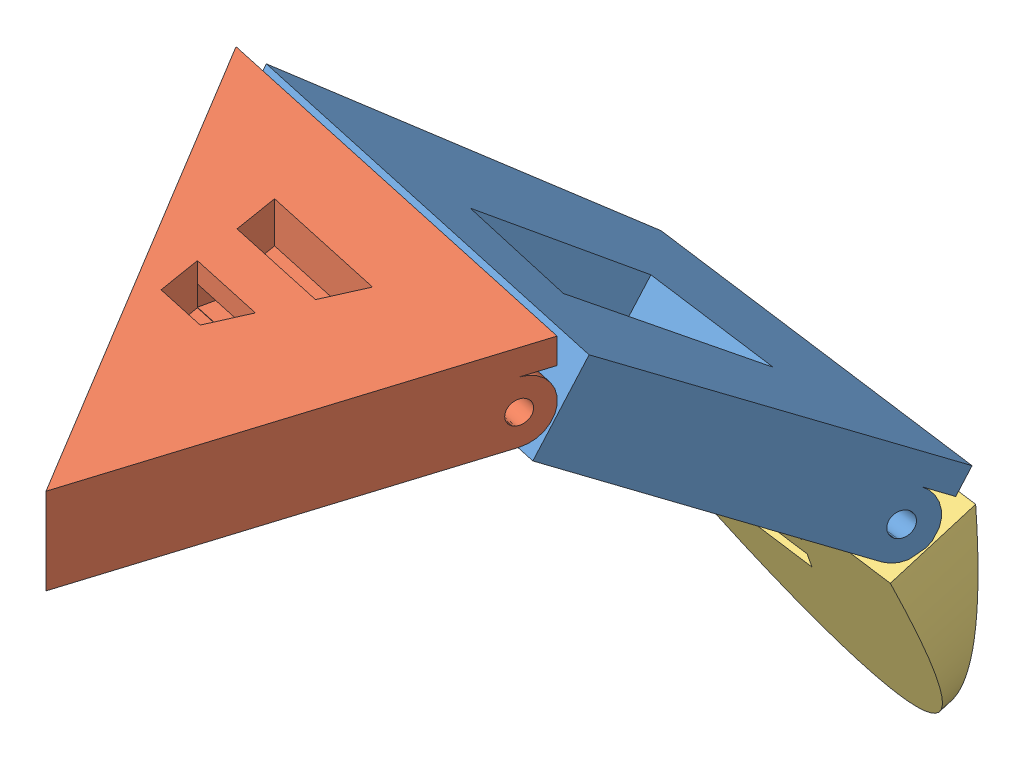
SolidWorks assembly FEar, configuration Default. Lengths in mm.
Overall size (62.96 54.67 83.83).
3 component instances, 3 part files, 4 mates.
Components (placement in the parent):
- FEar (2)-1: FEar (2) [Default] at (8.8939 48.3821 14.2362) x (0.992787 -0.115286 0.032908) z (0.032908 0.525979 0.84986) size (51.75 8.73 38.46)
- FEar (3)-1: FEar (3) [Default] at (-3.2487 61.5003 32.783) x (0.976812 0 0.214101) z (-0.214101 0 0.976812) size (41.89 8.6 40.49)
- FEar (1)-1: FEar (1) [Default] at (9.4915 54.9534 14.362) x (0.992787 -0.115286 0.032908) z (0.09412 0.919477 0.381711) size (35.34 15.1 27.6)
Mates (geometry in assembly coordinates):
- Concentric1: concentric anti-aligned: circle of FEar (2)-1; circle of FEar (3)-1
- Coincident4: coincident anti-aligned: plane of FEar (2)-1 through (-1.4064 74.2075 24.3776) normal (-0.976812 0 -0.214101); plane of FEar (3)-1 through (-3.2487 76.7403 32.783) normal (0.976812 0 0.214101)
- Concentric2: concentric anti-aligned: circle of FEar (2)-1; circle of FEar (1)-1
- Coincident5: coincident anti-aligned: plane of FEar (2)-1 through (29.5702 59.0271 6.8474) normal (-0.992787 0.115286 -0.032908); plane of FEar (1)-1 through (29.513 57.5114 3.2634) normal (0.992787 -0.115286 0.032908)
